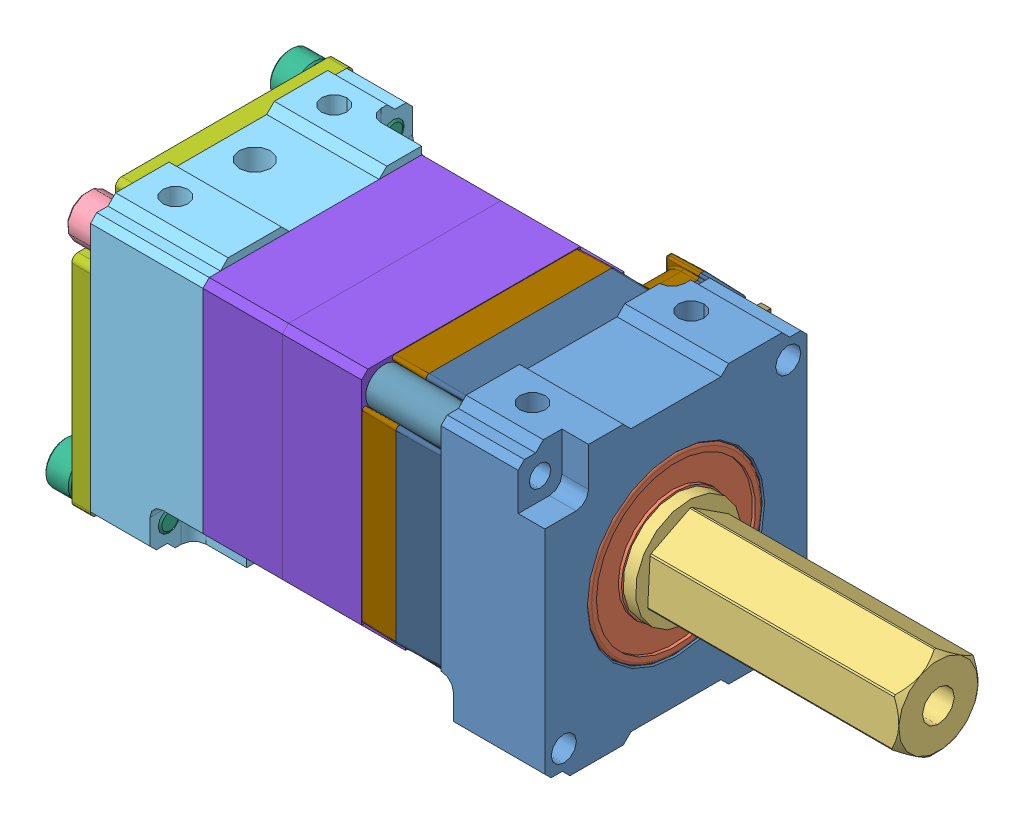
SolidWorks assembly VersaPlanetary_v2_Two_Stage_with_Encoder, configuration Default. Lengths in mm.
Overall size (121.79 44.49 58.95).
22 component instances, 16 part files, 29 mates.
Components (placement in the parent):
- 217-2625-026 Rev1-1: 217-2625-026 Rev1 [Default] at (25.4052 43.6717 -41.1353) x (0 -1 0) z (-1 0 0) size (44.45 42 18.13)
- 217-2742-001 Rev4-1: 217-2742-001 Rev4 [Default] at (30.4052 43.6717 -41.1353) x (1 0 0) z (0 -0.092627 0.995701) size (7 28 28)
- 217-2742-001 Rev4-2: 217-2742-001 Rev4 [Default] at (41.5302 43.6717 -41.1353) size (7 28 28)
- 217-2625-003 Rev1-1: 217-2625-003 Rev1 [Default] at (40.7778 43.6717 -41.1353) x (0 -0.891414 -0.45319) z (1 0 0) size (17 17 64.12)
- 832-2250-Base-Kit-Screw_SSA0832-0500ZC-1: 832-2250-Base-Kit-Screw_SSA0832-0500ZC [Default] at (-24.1948 26.1717 -58.6353) x (0 -0.767799 -0.640691) z (0 0.640691 -0.767799) size (6.73 61.21 6.73)
- 832-2250-Base-Kit-Screw_SSA0832-0500ZC-2: 832-2250-Base-Kit-Screw_SSA0832-0500ZC [Default] at (-24.1948 61.1717 -23.6353) x (0 0.961307 0.275478) z (0 -0.275478 0.961307) size (6.73 61.21 6.73)
- 217-2625-025 Rev1-1: 217-2625-025 Rev1 [Default] at (-16.6948 43.6717 -41.1353) x (0 -1 0) z (-1 0 0) size (44.45 42 18)
- 217-4649-002 Rev1_SSA0832-0500ZC-1: 217-4649-002 Rev1_SSA0832-0500ZC [Default] at (-27.1948 25.7111 -23.1748) x (0 0.33842 -0.940995) z (0 0.940995 0.33842) size (6.73 16.76 6.73)
- 217-4649-002 Rev1_SSA0832-0500ZC-2: 217-4649-002 Rev1_SSA0832-0500ZC [Default] at (-27.1948 61.6322 -59.0958) x (0 -0.308932 -0.951084) z (0 0.951084 -0.308932) size (6.73 16.76 6.73)
- 217-2822-003 Rev4-1: 217-2822-003 Rev4 [Default] at (-25.6948 43.6717 -41.1353) x (0 -1 0) z (-1 0 0) size (42 42 4.8)
- 217-2816-001 Rev1-1: 217-2816-001 Rev1 [Default] at (12.8552 43.6717 -41.1353) x (0 -1 0) z (1 0 0) size (42 42 14.5)
- 217-2816-001 Rev1-2: 217-2816-001 Rev1 [Default] at (0.1552 43.6717 -41.1353) x (0 -1 0) z (1 0 0) size (42 42 14.5)
- VersaPlanetary_Integrated_Encoder_217-5046-1: VersaPlanetary_Integrated_Encoder_217-5046 [Default] at (24.7052 43.6717 -41.1353) x (0 0 1) z (-1 0 0) size (58.21 43.13 18.16)
  - 217-4783-001 Rev3-1: 217-4783-001 Rev3 [Default] at (0 0 2.75) size (53.55 42 11.11)
  - 217-4783-002 Rev7_Sealed Config-1: 217-4783-002 Rev7_Sealed Config [Default] at (0 0 -7.2) x (0 1 0) z (0 0 1) size (42 51.56 9.32)
  - 217-4783-008 Rev2-1: 217-4783-008 Rev2 [Default] at (-20.05 0 2.2) x (0.307149 -0.951661 0) z (0.951661 0.307149 0) size (5 4 5)
  - PCBA Rev3-1: PCBA Rev3 [Default] at (-20.05 0 -2.1252) x (0 1 0) z (-1 0 0) size (15.93 10.15 24.58)
  - 217-2788-001 Rev3_57155K375-1: 217-2788-001 Rev3_57155K375 [Default] at (-20.05 0 3.8125) x (-0.99574 0.092202 0) z (0 0 1) size (9.53 9.53 3.17)
  - 217-4783-006 Rev3-1: 217-4783-006 Rev3 [Default] at (17.5 17.5 -0.85) x (-0.867641 0.497191 0) z (0 0 1) size (5.9 5.9 12.7)
  - 217-4783-006 Rev3-2: 217-4783-006 Rev3 [Default] at (-17.5 -17.5 -0.85) x (0.825154 -0.564908 0) z (0 0 1) size (5.9 5.9 12.7)
  - 217-4783-007 Rev1-1: 217-4783-007 Rev1 [Default] at (-16.45 0 -5.2) x (0 1 0) z (0 0 1) size (6 10.71 3.56)
  - 217-4783-003 Rev4-1: 217-4783-003 Rev4 [Default] at (-20.05 0 -1.02) x (0 1 0) z (0 0 1) size (23.4 21.71 4.21)
Mates (geometry in assembly coordinates):
- Concentric1: concentric aligned: cylinder of 217-2625-026 Rev1-1 through (48.5302 43.6717 -41.1353) axis (-1 0 0) radius 13.995; cylinder of 217-2742-001 Rev4-2 through (41.5302 43.6717 -41.1353) axis (-1 0 0) radius 14
- Coincident2: coincident aligned: plane of 217-2625-026 Rev1-1 through (48.5302 65.8967 -18.9103) normal (1 0 0); plane of 217-2742-001 Rev4-2 through (48.5302 56.4217 -41.1353) normal (1 0 0)
- Concentric2: concentric aligned: cylinder of 217-2625-026 Rev1-1 through (48.5302 43.6717 -41.1353) axis (-1 0 0) radius 13.995; cylinder of 217-2742-001 Rev4-1 through (30.4052 43.6717 -41.1353) axis (-1 0 0) radius 14
- Coincident3: coincident aligned: plane of 217-2625-026 Rev1-1 through (30.4052 43.6717 -41.1353) normal (-1 0 0); plane of 217-2742-001 Rev4-1 through (30.4052 57.6115 -39.8385) normal (-1 0 0)
- Concentric3: concentric aligned: cylinder of 217-2742-001 Rev4-2 through (41.5302 43.6717 -41.1353) axis (-1 0 0) radius 7.5; cylinder of 217-2625-003 Rev1-1 through (50.5302 43.6717 -41.1353) axis (-1 0 0) radius 7.4955
- Coincident4: coincident anti-aligned: plane of 217-2742-001 Rev4-2 through (48.5302 51.1717 -41.1353) normal (1 0 0); plane of 217-2625-003 Rev1-1 through (48.5302 43.6717 -41.1353) normal (-1 0 0)
- Concentric4: concentric aligned: circle of 217-2625-026 Rev1-1; circle of 217-2816-001 Rev1-1
- Parallel1: parallel aligned: plane of 217-2625-026 Rev1-1 through (30.4052 22.6717 -20.1353) normal (0 0 1); plane of 217-2816-001 Rev1-1 through (19.2051 70.3619 -22.5097) normal (0 0 1)
- Concentric5: concentric aligned: circle of 217-2816-001 Rev1-1; circle of 217-2816-001 Rev1-2
- Coincident6: coincident anti-aligned: plane of 217-2816-001 Rev1-1 through (6.5051 28.3619 -64.5097) normal (-1 0 0); plane of 217-2816-001 Rev1-2 through (-7.538 22.6717 -62.1353) normal (1 0 0)
- Parallel2: parallel aligned: plane of 217-2816-001 Rev1-1 through (19.2051 70.3619 -22.5097) normal (0 0 1); plane of 217-2816-001 Rev1-2 through (-7.538 64.6717 -20.1353) normal (0 0 1)
- Concentric6: concentric anti-aligned: circle of 217-2625-025 Rev1-1; circle of 217-2816-001 Rev1-2
- Coincident7: coincident anti-aligned: plane of 217-2625-025 Rev1-1 through (-20.238 65.8967 -18.9103) normal (1 0 0); plane of 217-2816-001 Rev1-2 through (-20.238 22.6717 -62.1353) normal (-1 0 0)
- Parallel3: parallel aligned: plane of 217-2625-025 Rev1-1 through (-20.238 64.6717 -20.1353) normal (0 0 1); plane of 217-2816-001 Rev1-2 through (-7.538 64.6717 -20.1353) normal (0 0 1)
- Concentric7: concentric anti-aligned: circle of 217-2625-025 Rev1-1; circle of 217-2822-003 Rev4-1
- Coincident9: coincident anti-aligned: plane of 217-2625-025 Rev1-1 through (-38.238 21.4467 -18.9103) normal (-1 0 0); plane of 217-2822-003 Rev4-1 through (-38.238 43.6717 -41.1353) normal (1 0 0)
- Parallel4: parallel aligned: plane of 217-2625-025 Rev1-1 through (-20.238 64.6717 -20.1353) normal (0 0 1); plane of 217-2822-003 Rev4-1 through (-41.238 43.6717 -20.1353) normal (0 0 1)
- Concentric8: concentric: circle of 217-2625-026 Rev1-1; circle of VersaPlanetary_Integrated_Encoder_217-5046-1/217-4783-002 Rev7_Sealed Config-1
- Coincident10: coincident: plane of 217-2625-026 Rev1-1 through (31.9052 43.6717 -41.1353) normal (-1 0 0); plane of VersaPlanetary_Integrated_Encoder_217-5046-1/217-4783-006 Rev3-1 through (31.9052 58.6121 -25.102) normal (1 0 0)
- Concentric9: concentric anti-aligned: circle of 217-2625-026 Rev1-1; circle of VersaPlanetary_Integrated_Encoder_217-5046-1/217-4783-006 Rev3-1
- Coincident11: coincident anti-aligned: plane of 217-2816-001 Rev1-1 through (19.2052 22.6717 -62.1353) normal (1 0 0); plane of VersaPlanetary_Integrated_Encoder_217-5046-1/217-4783-006 Rev3-1 through (19.2052 58.6121 -25.102) normal (-1 0 0)
- Concentric10: concentric: cylinder of 832-2250-Base-Kit-Screw_SSA0832-0500ZC-2 through (32.9552 61.1717 -23.6353) axis (-1 0 0) radius 2.0828; cylinder of 217-2625-025 Rev1-1 through (-24.1948 61.1717 -23.6353) axis (-1 0 0) radius 2.2479
- Coincident12: coincident anti-aligned: plane of 832-2250-Base-Kit-Screw_SSA0832-0500ZC-2 through (-24.1948 61.1717 -23.6353) normal (1 0 0); plane of 217-2625-025 Rev1-1 through (-24.1948 21.4467 -18.9103) normal (-1 0 0)
- Concentric11: concentric: cylinder of 832-2250-Base-Kit-Screw_SSA0832-0500ZC-1 through (32.9552 26.1717 -58.6353) axis (-1 0 0) radius 2.0828; cylinder of 217-2625-025 Rev1-1 through (-24.1948 26.1717 -58.6353) axis (-1 0 0) radius 2.2479
- Coincident13: coincident anti-aligned: plane of 832-2250-Base-Kit-Screw_SSA0832-0500ZC-1 through (-24.1948 26.1717 -58.6353) normal (1 0 0); plane of 217-2625-025 Rev1-1 through (-24.1948 21.4467 -18.9103) normal (-1 0 0)
- Concentric12: concentric: cylinder of 217-2625-025 Rev1-1 through (6.5052 61.6322 -59.0958) axis (1 0 0) radius 1.7272; cylinder of 217-4649-002 Rev1_SSA0832-0500ZC-2 through (-14.4948 61.6322 -59.0958) axis (-1 0 0) radius 2.0828
- Coincident14: coincident anti-aligned: plane of 217-4649-002 Rev1_SSA0832-0500ZC-2 through (-27.1948 61.6322 -59.0958) normal (1 0 0); plane of 217-2822-003 Rev4-1 through (-27.1948 43.6717 -41.1353) normal (-1 0 0)
- Concentric13: concentric: cylinder of 217-2625-025 Rev1-1 through (6.5052 25.7111 -23.1748) axis (1 0 0) radius 1.7272; cylinder of 217-4649-002 Rev1_SSA0832-0500ZC-1 through (-14.4948 25.7111 -23.1748) axis (-1 0 0) radius 2.0828
- Coincident15: coincident anti-aligned: plane of 217-4649-002 Rev1_SSA0832-0500ZC-1 through (-27.1948 25.7111 -23.1748) normal (1 0 0); plane of 217-2822-003 Rev4-1 through (-27.1948 43.6717 -41.1353) normal (-1 0 0)
